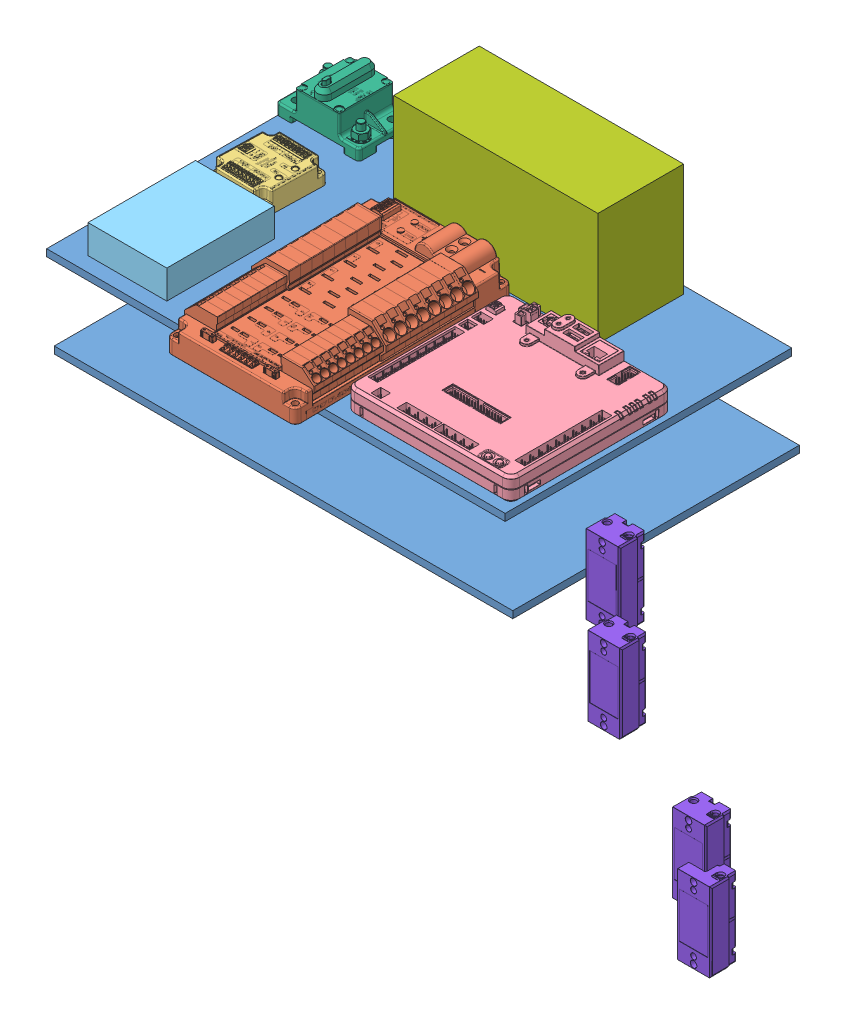
SolidWorks assembly e-assembley, configuration Default. Lengths in mm.
Overall size (787.29 180.85 452.85).
12 component instances, 8 part files, 13 mates.
Components (placement in the parent):
- e-board-1: e-board [Default] at (-262.5621 11.9711 141.5165) size (406.4 6.22 254)
- PDP-1: PDP [Default] at (-73.6073 26.1531 75.4875) x (-0.000021 -0.017452 0.999848) z (-0.999999 0.001193 0) size (192.68 36.15 120.93)
- VRM-1: VRM [Default] at (-212.47 25.3254 -5.1761) x (-0.026397 0 0.999652) z (-0.999652 0 -0.026397) size (56.39 19.92 51.56)
- Roborio-1: Roborio [Default] at (67.9878 27.8461 61.997) x (1 0 0) z (0 1 0) size (146.27 143.19 36.83)
- radio b;ock-1: radio b;ock [Default] at (-238.9168 18.1941 128.5325) size (69.85 25.4 95.25)
- Breaker-1: Breaker [Default] at (-225.5957 24.7582 -85.5314) size (73.72 42.2 48.95)
- Battery-1: Battery [Default] at (-126.424 -48.6762 -105.7767) x (0 0 1) z (-1 0 0) size (75.95 166.88 181.1)
- e-board-2: e-board [Default] at (-251.3899 -54.8992 145.942) size (406.4 6.22 254)
- Speed Controller-1: Speed Controller [Default] at (215.6016 -6.5721 111.5569) size (30.12 70.11 24.39)
- Speed Controller-2: Speed Controller [Default] at (495.5522 21.3701 314.8757) size (30.12 70.11 24.39)
- Speed Controller-3: Speed Controller [Default] at (273.1607 -27.6621 167.6967) size (30.12 70.11 24.39)
- Speed Controller-4: Speed Controller [Default] at (509.6687 -14.1429 324.5263) size (30.12 70.11 24.39)
Mates (geometry in assembly coordinates):
- Coincident1: coincident: plane of e-board-1 through (-262.5621 18.1941 141.5165) normal (0 1 0); plane of PDP-1 through (-131.0211 17.9364 167.3811) normal (-0.001193 -0.999847 -0.017452)
- Parallel1: parallel: plane of e-board-1 through (-262.5621 18.1941 141.5165) normal (0 0 1); plane of PDP-1 through (-16.2132 17.7994 167.3811) normal (0 0 1)
- Coincident2: coincident anti-aligned: plane of e-board-1 through (-262.5621 18.1941 141.5165) normal (0 1 0); plane of VRM-1 through (-193.5458 18.1941 18.6761) normal (0 -1 0)
- Parallel2: parallel aligned: plane of e-board-1 through (-262.5621 18.1941 141.5165) normal (0 1 0); plane of radio b;ock-1 through (-238.9168 43.5941 128.5325) normal (0 1 0)
- Coincident3: coincident anti-aligned: plane of e-board-1 through (-262.5621 18.1941 141.5165) normal (0 1 0); plane of radio b;ock-1 through (-238.9168 18.1941 128.5325) normal (0 -1 0)
- Coincident4: coincident aligned: plane of e-board-1 through (-262.5621 18.1941 141.5165) normal (0 1 0); plane of Roborio-1 through (-5.5242 18.1941 133.9636) normal (0 1 0)
- Parallel3: parallel: line of e-board-1 through (143.8379 18.1941 141.5165) axis (0 0 -1); plane of Roborio-1 through (141.0636 20.4262 128.5256) normal (-1 0 0)
- Parallel4: parallel aligned: plane of e-board-1 through (-262.5621 18.1941 141.5165) normal (0 1 0); plane of Battery-1 through (-126.424 118.2018 -105.7767) normal (0 1 0)
- Parallel8: parallel anti-aligned: plane of Battery-1 through (-126.424 -48.6762 -105.7767) normal (0 -1 0); plane of e-board-2 through (-251.3899 -48.6762 145.942) normal (0 1 0)
- Coincident7: coincident anti-aligned: plane of Battery-1 through (-126.424 -48.6762 -105.7767) normal (0 -1 0); plane of e-board-2 through (-251.3899 -48.6762 145.942) normal (0 1 0)
- Parallel9: parallel aligned: plane of e-board-1 through (-262.5621 18.1941 141.5165) normal (-1 0 0); plane of e-board-2 through (-251.3899 -48.6762 145.942) normal (-1 0 0)
- Parallel10: parallel aligned: plane of Battery-1 through (-126.424 118.2018 -105.7767) normal (0 0 -1); plane of e-board-2 through (-251.3899 -48.6762 -108.058) normal (0 0 -1)
- Parallel11: parallel aligned: plane of e-board-1 through (-262.5621 18.1941 141.5165) normal (-1 0 0); plane of e-board-2 through (-251.3899 -48.6762 145.942) normal (-1 0 0)
